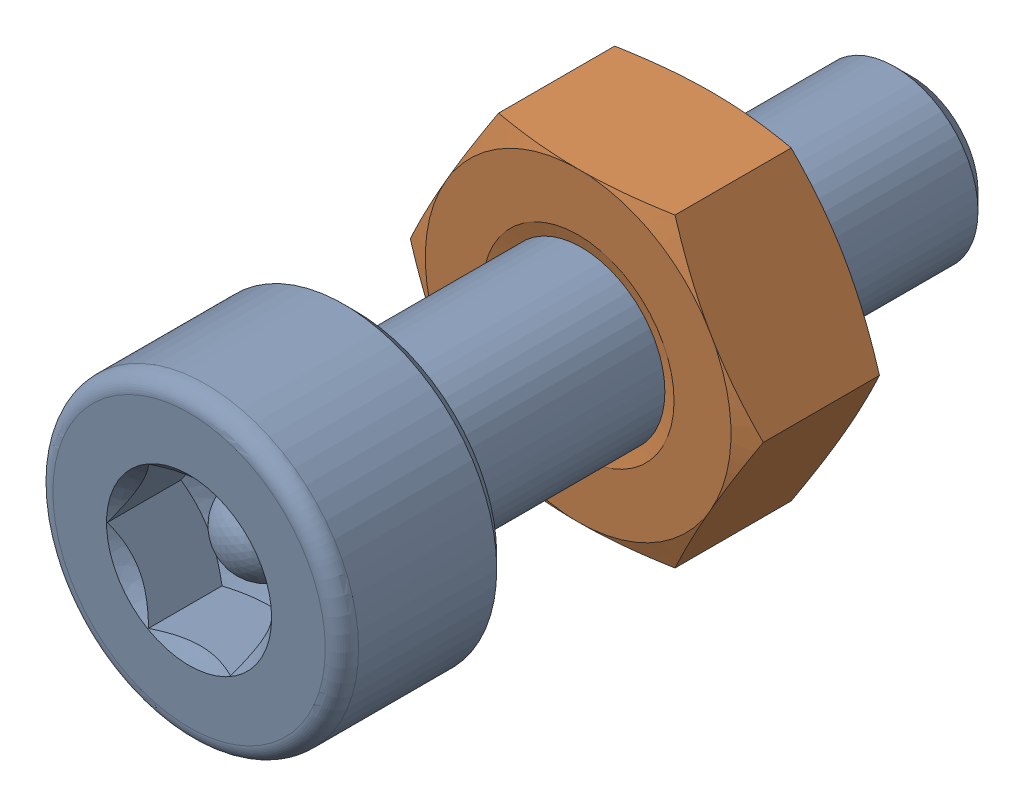
SolidWorks assembly Screw and Nut M3x010_013-1, configuration Varsayılan. Lengths in mm.
Overall size (6.35 5.5 13.14).
2 component instances, 2 part files, 0 mates.
Components (placement in the parent):
- M3x10-Screw012-1-1: M3x10-Screw012-1 [Varsayılan] at origin size (5.5 5.5 13.14)
- M3-Nut044-1-1: M3-Nut044-1 [Varsayılan] at (0 0 -4) x (-1 0 0) z (0 0 -1) size (6.35 5.5 2.4)
